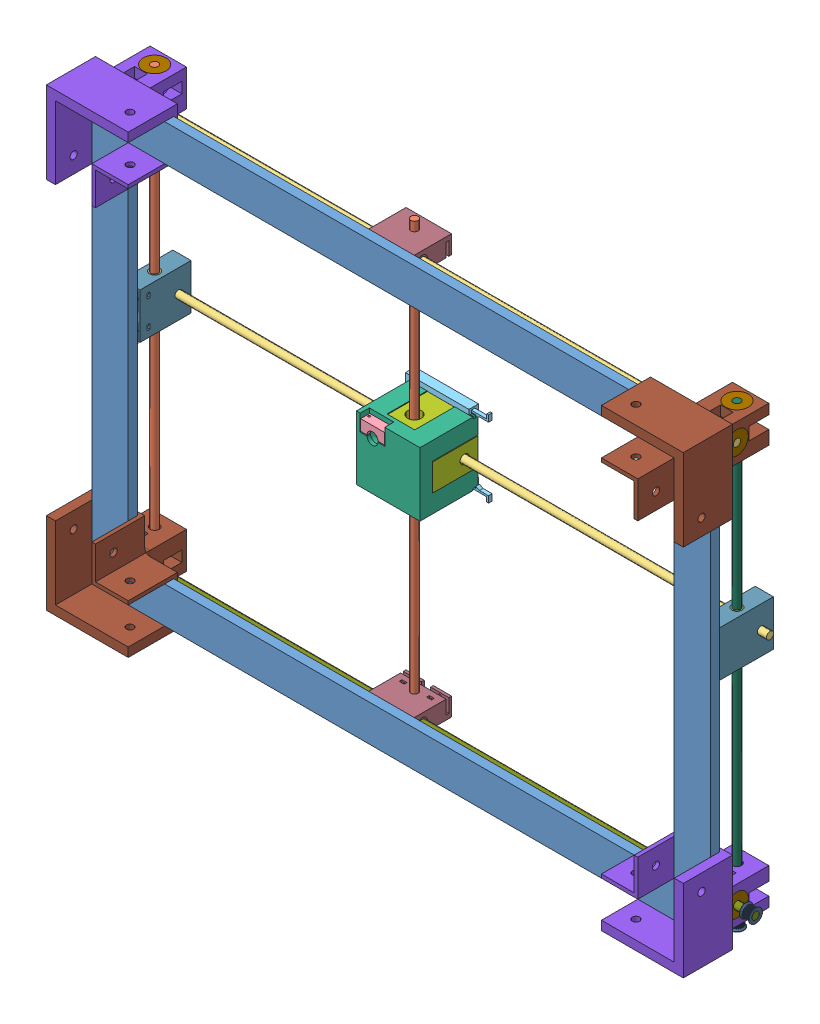
SolidWorks assembly Assemblage_XY, configuration Défaut. Lengths in mm.
Overall size (711.84 510.5 125.29).
50 component instances, 16 part files, 70 mates.
Components (placement in the parent):
- Cadre_XY-1: Cadre_XY [Défaut] at (379.0068 -247.2078 675) size (680 480 10)
- AXE_8X480-2: AXE_8X480 [Défaut] at (-280.9932 -247.2078 636) x (0.987721 0 0.156231) z (0 1 0) size (8 8 480)
- AXE_8X680-1: AXE_8X680 [Défaut] at (379.0068 212.7922 656) x (0 0.013067 0.999915) z (-1 0 0) size (8 8 680)
- AXE_8X480-3: AXE_8X480 [Défaut] at (8.3254 232.7922 639.7) x (0.999527 0 0.030742) z (0 -1 0) size (8 8 480)
- AXE_8X680-3: AXE_8X680 [Défaut] at (-300.9932 11.1319 619.7) x (0 -0.696158 -0.717888) z (1 0 0) size (8 8 680)
- P3DMIPC-Tête_complete-1: P3DMIPC-Tête_complete [Défaut] at (-35.8673 24.5019 635.2981) x (0 1 0) z (1 0 0) size (84 69 89)
  - P3DMIPC-Clip_Buse_E3D-1: P3DMIPC-Clip_Buse_E3D [Défaut] at (17.0518 23.4109 40.0035) x (1 0 0) z (0 1 0) size (12 26 10)
  - P3DMIPC-Clip_tête-1: P3DMIPC-Clip_tête [Défaut] at (26.9018 -25.0891 4.5597) x (1 0 0) z (0 -1 0) size (84 89 10.5)
  - P3DMIPC-Porte_Buse_E3DX1-1: P3DMIPC-Porte_Buse_E3DX1 [Défaut] at (22.03 33.4019 79.1927) x (0 0 1) z (0 -1 0) size (70 70 64)
  - P3DMIPC-Chariot-1: P3DMIPC-Chariot [Défaut] at (-48.37 -30.5981 79.1927) size (70 50 70)
- Angle_magique_G-1: Angle_magique_G [Défaut] at (379.0068 -247.2078 675) x (-1 0 0) z (0 0 -1) size (91.34 90 104)
- F608ZZ-1: F608ZZ [Défaut] at (372.0068 -227.2078 656) x (0 -0.924225 -0.381849) z (1 0 0) size (25 25 7)
- Angle_magique_G-4: Angle_magique_G [Défaut] at (-300.9932 232.7922 675) x (1 0 0) z (0 0 -1) size (91.34 90 104)
- pulley_gt2_3mm_20t-10: pulley_gt2_3mm_20t [Défaut] at (-280.9932 209.5422 636) x (0.106795 0 0.994281) z (0 1 0) size (15 15 10.5)
- pulley_gt2_3mm_20t-11: pulley_gt2_3mm_20t [Défaut] at (-277.7432 212.7922 656) x (0 0.106795 0.994281) z (-1 0 0) size (15 15 10.5)
- pulley_gt2_3mm_20t-12: pulley_gt2_3mm_20t [Défaut] at (-280.9932 -236.4578 636) x (-0.771074 0 0.636745) z (0 1 0) size (15 15 10.5)
- pulley_gt2_3mm_20t-13: pulley_gt2_3mm_20t [Défaut] at (-277.7432 -227.2078 656) x (0 0.106795 0.994281) z (-1 0 0) size (15 15 10.5)
- pulley_gt2_3mm_20t-15: pulley_gt2_3mm_20t [Défaut] at (359.0068 222.0422 636) x (-0.106795 0 0.994281) z (0 -1 0) size (15 15 10.5)
- pulley_gt2_3mm_20t-16: pulley_gt2_3mm_20t [Défaut] at (368.2568 212.7922 656) x (0 0.106795 0.994281) z (-1 0 0) size (15 15 10.5)
- F608ZZ-2: F608ZZ [Défaut] at (-280.9932 225.7922 636) x (-0.546944 0 0.837169) z (0 1 0) size (25 25 7)
- F608ZZ-3: F608ZZ [Défaut] at (-293.9932 212.7922 656) x (0 0 1) z (-1 0 0) size (25 25 7)
- F608ZZ-4: F608ZZ [Défaut] at (-293.9932 -227.2078 656) x (0 0 1) z (-1 0 0) size (25 25 7)
- F608ZZ-5: F608ZZ [Défaut] at (-280.9932 -240.2078 636) x (-0.924225 0 -0.381849) z (0 -1 0) size (25 25 7)
- F608ZZ-6: F608ZZ [Défaut] at (359.0068 -240.2078 636) x (-0.546944 0 0.837169) z (0 -1 0) size (25 25 7)
- F608ZZ-7: F608ZZ [Défaut] at (372.0068 212.7922 656) x (0 0 1) z (1 0 0) size (25 25 7)
- F608ZZ-8: F608ZZ [Défaut] at (359.0068 225.7922 636) x (0 0 1) z (0 1 0) size (25 25 7)
- Angle_magique_D-1: Angle_magique_D [Défaut] at (-300.9932 -247.2078 675) x (0 1 0) z (0 0 -1) size (90 91.34 104)
- Angle_magique_D-2: Angle_magique_D [Défaut] at (379.0068 232.7922 675) x (0 -1 0) z (0 0 -1) size (90 91.34 104)
- Assemblage_glissière_block_belt_palier_AR-1: Assemblage_glissière_block_belt_palier_AR [Défaut] at (128.8503 -186.4667 609.4689) x (0 -1 0) z (-1 0 0) size (20 42 50)
  - ultimaker_cuivre_fritté_douille_8mmx11mmx22 mm-1: ultimaker_cuivre_fritté_douille_8mmx11mmx22 mm [Défaut] at (40.7411 46.5311 95.5249) size (11 11 22)
  - ultimaker_cuivre_fritté_douille_8mmx11mmx22 mm-2: ultimaker_cuivre_fritté_douille_8mmx11mmx22 mm [Défaut] at (40.7411 46.5311 123.5249) size (11 11 22)
  - Glisière_block_belt_AR-2: Glisière_block_belt_AR [Défaut] at (50.7411 14.5311 95.5249) size (20 42 50)
- Assemblage_glissière_block_belt_palier_AR-2: Assemblage_glissière_block_belt_palier_AR [Défaut] at (-112.1995 172.0511 609.4689) x (0 1 0) z (1 0 0) size (20 42 50)
  - ultimaker_cuivre_fritté_douille_8mmx11mmx22 mm-1: ultimaker_cuivre_fritté_douille_8mmx11mmx22 mm [Défaut] at (40.7411 46.5311 95.5249) size (11 11 22)
  - ultimaker_cuivre_fritté_douille_8mmx11mmx22 mm-2: ultimaker_cuivre_fritté_douille_8mmx11mmx22 mm [Défaut] at (40.7411 46.5311 123.5249) size (11 11 22)
  - Glisière_block_belt_AR-2: Glisière_block_belt_AR [Défaut] at (50.7411 14.5311 95.5249) size (20 42 50)
- pulley_gt2_3mm_20t-17: pulley_gt2_3mm_20t [Défaut] at (368.2568 -227.2078 656) x (0 0.106795 0.994281) z (-1 0 0) size (15 15 10.5)
- pulley_gt2_3mm_20t-18: pulley_gt2_3mm_20t [Défaut] at (359.0068 -223.9578 636) x (0.203502 0 0.979074) z (0 -1 0) size (15 15 10.5)
- Assemblage_glissière_block_belt_palier_GD-1: Assemblage_glissière_block_belt_palier_GD [Défaut] at (364.4936 -63.8681 626.6132) x (-1 0 0) z (0 1 0) size (20 60 50)
  - Glisière_block_belt_GD-1: Glisière_block_belt_GD [Défaut] at (15.4869 -20.6132 50) size (20 60 50)
  - ultimaker_cuivre_fritté_douille_8mmx11mmx22 mm-1: ultimaker_cuivre_fritté_douille_8mmx11mmx22 mm [Défaut] at (5.4869 9.3868 50) size (11 11 22)
  - ultimaker_cuivre_fritté_douille_8mmx11mmx22 mm-2: ultimaker_cuivre_fritté_douille_8mmx11mmx22 mm [Défaut] at (5.4869 9.3868 78) size (11 11 22)
- Assemblage_glissière_block_belt_palier_GD-2: Assemblage_glissière_block_belt_palier_GD [Défaut] at (-286.4801 86.1319 626.6132) x (1 0 0) z (0 -1 0) size (20 60 50)
  - Glisière_block_belt_GD-1: Glisière_block_belt_GD [Défaut] at (15.4869 -20.6132 50) size (20 60 50)
  - ultimaker_cuivre_fritté_douille_8mmx11mmx22 mm-1: ultimaker_cuivre_fritté_douille_8mmx11mmx22 mm [Défaut] at (5.4869 9.3868 50) size (11 11 22)
  - ultimaker_cuivre_fritté_douille_8mmx11mmx22 mm-2: ultimaker_cuivre_fritté_douille_8mmx11mmx22 mm [Défaut] at (5.4869 9.3868 78) size (11 11 22)
- AXE_8X500_Moteur-1: AXE_8X500_Moteur [Défaut] at (359.0068 -267.7078 636) x (0.283264 0 -0.959042) z (0 1 0) size (8 8 500.5)
- AXE_8X700_Moteur-1: AXE_8X700_Moteur [Défaut] at (399.5068 -227.2078 656) x (0 0 1) z (-1 0 0) size (8 8 700.5)
- pulley_gt2_3mm_20t-19: pulley_gt2_3mm_20t [Défaut] at (359.0068 -256.2078 636) x (0.203502 0 0.979074) z (0 -1 0) size (15 15 10.5)
- pulley_gt2_3mm_20t-20: pulley_gt2_3mm_20t [Défaut] at (388.0068 -227.2078 656) x (0 0.203502 0.979074) z (1 0 0) size (15 15 10.5)
Mates (geometry in assembly coordinates):
- Coaxiale1: concentric anti-aligned: cylinder of AXE_8X680-3 through (379.0068 11.1319 619.7) axis (-1 0 0) radius 4; cylinder of P3DMIPC-Tête_complete-1/P3DMIPC-Chariot-1 through (39.3254 11.1319 619.7) axis (1 0 0) radius 5
- Coaxiale2: concentric anti-aligned: cylinder of AXE_8X480-3 through (8.3254 -247.2078 639.7) axis (0 1 0) radius 4; cylinder of P3DMIPC-Tête_complete-1/P3DMIPC-Chariot-1 through (8.3254 -19.8681 639.7) axis (0 -1 0) radius 5
- Coïncidente14: coincident anti-aligned: plane of Cadre_XY-1 through (379.0068 -247.2078 675) normal (0 0 -1); plane of Angle_magique_G-1 through (379.0068 -247.2078 675) normal (0 0 1)
- Coïncidente15: coincident anti-aligned: plane of Cadre_XY-1 through (379.0068 -247.2078 685) normal (1 0 0); plane of Angle_magique_G-1 through (379.0068 -247.2078 725) normal (-1 0 0)
- Coïncidente16: coincident anti-aligned: plane of Cadre_XY-1 through (379.0068 -247.2078 685) normal (0 -1 0); plane of Angle_magique_G-1 through (299.0068 -247.2078 725) normal (0 1 0)
- Coïncidente27: coincident anti-aligned: plane of Cadre_XY-1 through (379.0068 -247.2078 675) normal (0 0 -1); plane of Angle_magique_G-4 through (-300.9932 232.7922 675) normal (0 0 1)
- Coïncidente28: coincident anti-aligned: plane of Cadre_XY-1 through (379.0068 232.7922 685) normal (0 1 0); plane of Angle_magique_G-4 through (-220.9932 232.7922 725) normal (0 -1 0)
- Coïncidente29: coincident anti-aligned: plane of Cadre_XY-1 through (-300.9932 -247.2078 685) normal (-1 0 0); plane of Angle_magique_G-4 through (-300.9932 232.7922 725) normal (1 0 0)
- Coaxiale17: concentric anti-aligned: cylinder of AXE_8X680-1 through (-300.9932 212.7922 656) axis (1 0 0) radius 4; cylinder of pulley_gt2_3mm_20t-11 through (-277.7432 212.7922 656) axis (-1 0 0) radius 4
- Coaxiale18: concentric aligned: cylinder of AXE_8X680-1 through (-300.9932 212.7922 656) axis (1 0 0) radius 4; cylinder of Angle_magique_G-4 through (-310.9932 212.7922 656) axis (1 0 0) radius 5
- Coïncidente30: coincident aligned: plane of Cadre_XY-1 through (-300.9932 -247.2078 685) normal (-1 0 0); plane of AXE_8X680-1 through (-300.9932 212.7922 656) normal (-1 0 0)
- Distance2: distance = 2.75 mm anti-aligned: plane of pulley_gt2_3mm_20t-11 through (-278.7432 212.7922 656) normal (1 0 0); plane of Angle_magique_G-4 through (-275.9932 192.7922 621) normal (-1 0 0)
- Coaxiale19: concentric anti-aligned: cylinder of AXE_8X680-1 through (-300.9932 212.7922 656) axis (1 0 0) radius 4; cylinder of pulley_gt2_3mm_20t-16 through (368.2568 212.7922 656) axis (-1 0 0) radius 4
- Coaxiale24: concentric aligned: cylinder of AXE_8X480-2 through (-280.9932 232.7922 636) axis (0 -1 0) radius 4; cylinder of Angle_magique_G-4 through (-280.9932 232.7923 636) axis (0 -1 0) radius 5
- Coaxiale25: concentric anti-aligned: cylinder of AXE_8X480-2 through (-280.9932 232.7922 636) axis (0 -1 0) radius 4; cylinder of pulley_gt2_3mm_20t-10 through (-280.9932 209.5422 636) axis (0 1 0) radius 4
- Coïncidente34: coincident aligned: plane of Cadre_XY-1 through (379.0068 232.7922 685) normal (0 1 0); plane of AXE_8X480-2 through (-280.9932 232.7922 636) normal (0 1 0)
- Distance4: distance = 2.75 mm anti-aligned: plane of pulley_gt2_3mm_20t-10 through (-280.9932 210.5422 636) normal (0 -1 0); plane of Angle_magique_G-4 through (-275.9932 207.7922 621) normal (0 1 0)
- Coaxiale26: concentric anti-aligned: cylinder of AXE_8X480-2 through (-280.9932 232.7922 636) axis (0 -1 0) radius 4; cylinder of pulley_gt2_3mm_20t-12 through (-280.9932 -236.4578 636) axis (0 1 0) radius 4
- Coïncidente44: coincident anti-aligned: plane of Cadre_XY-1 through (379.0068 -247.2078 675) normal (0 0 -1); plane of Angle_magique_D-1 through (-300.9932 -247.2078 675) normal (0 0 1)
- Coïncidente45: coincident anti-aligned: plane of Cadre_XY-1 through (379.0068 -247.2078 685) normal (0 -1 0); plane of Angle_magique_D-1 through (-300.9932 -247.2078 725) normal (0 1 0)
- Coïncidente46: coincident anti-aligned: plane of Cadre_XY-1 through (-300.9932 -247.2078 685) normal (-1 0 0); plane of Angle_magique_D-1 through (-300.9932 -167.2078 725) normal (1 0 0)
- Distance10: distance = 2.75 mm anti-aligned: plane of Angle_magique_D-1 through (-260.9932 -222.2078 621) normal (0 -1 0); plane of pulley_gt2_3mm_20t-12 through (-280.9932 -224.9578 636) normal (0 1 0)
- Coïncidente51: coincident anti-aligned: plane of Cadre_XY-1 through (379.0068 -247.2078 675) normal (0 0 -1); plane of Angle_magique_D-2 through (379.0068 232.7922 675) normal (0 0 1)
- Coïncidente52: coincident anti-aligned: plane of Cadre_XY-1 through (379.0068 232.7922 685) normal (0 1 0); plane of Angle_magique_D-2 through (379.0068 232.7922 725) normal (0 -1 0)
- Coïncidente53: coincident anti-aligned: plane of Cadre_XY-1 through (379.0068 -247.2078 685) normal (1 0 0); plane of Angle_magique_D-2 through (379.0068 152.7922 725) normal (-1 0 0)
- Distance11: distance = 2.75 mm anti-aligned: plane of pulley_gt2_3mm_20t-15 through (359.0068 210.5422 636) normal (0 -1 0); plane of Angle_magique_D-2 through (339.0068 207.7922 621) normal (0 1 0)
- Distance12: distance = 2.75 mm anti-aligned: plane of Angle_magique_D-2 through (354.0068 207.7922 621) normal (1 0 0); plane of pulley_gt2_3mm_20t-16 through (356.7568 212.7922 656) normal (-1 0 0)
- Coaxiale39: concentric anti-aligned: cylinder of AXE_8X680-1 through (-300.9932 212.7922 656) axis (1 0 0) radius 4; cylinder of Assemblage_glissière_block_belt_palier_AR-2/ultimaker_cuivre_fritté_douille_8mmx11mmx22 mm-1 through (5.3254 212.7922 656) axis (-1 0 0) radius 4
- Coaxiale42: concentric anti-aligned: cylinder of AXE_8X480-3 through (8.3254 -247.2078 639.7) axis (0 1 0) radius 4; cylinder of Assemblage_glissière_block_belt_palier_AR-2/Glisière_block_belt_AR-2 through (8.3254 222.7922 639.7) axis (0 -1 0) radius 4
- Coaxiale43: concentric aligned: cylinder of AXE_8X480-3 through (8.3254 -247.2078 639.7) axis (0 1 0) radius 4; cylinder of Assemblage_glissière_block_belt_palier_AR-1/Glisière_block_belt_AR-2 through (8.3254 -237.2078 639.7) axis (0 1 0) radius 4
- Coaxiale50: concentric anti-aligned: cylinder of F608ZZ-7 through (377.5068 212.7922 656) axis (-1 0 0) radius 11; cylinder of Angle_magique_D-2 through (372.0068 212.7922 656) axis (1 0 0) radius 11
- Coïncidente63: coincident anti-aligned: plane of F608ZZ-7 through (372.0068 212.7922 656) normal (-1 0 0); plane of Angle_magique_D-2 through (372.0068 212.7922 656) normal (1 0 0)
- Coaxiale51: concentric anti-aligned: cylinder of F608ZZ-8 through (359.0068 231.2922 636) axis (0 -1 0) radius 11; cylinder of Angle_magique_D-2 through (359.0068 225.7922 636) axis (0 1 0) radius 11
- Coïncidente64: coincident anti-aligned: plane of F608ZZ-8 through (359.0068 225.7922 636) normal (0 -1 0); plane of Angle_magique_D-2 through (359.0068 225.7922 636) normal (0 1 0)
- Coïncidente65: coincident anti-aligned: plane of Angle_magique_G-4 through (-280.9932 225.7922 636) normal (0 1 0); plane of F608ZZ-2 through (-280.9932 225.7922 636) normal (0 -1 0)
- Coaxiale53: concentric anti-aligned: cylinder of Angle_magique_G-4 through (-280.9932 225.7922 636) axis (0 1 0) radius 11; cylinder of F608ZZ-2 through (-280.9932 231.2922 636) axis (0 -1 0) radius 11
- Coaxiale54: concentric anti-aligned: cylinder of Angle_magique_G-4 through (-293.9932 212.7922 656) axis (-1 0 0) radius 11; cylinder of F608ZZ-3 through (-299.4932 212.7922 656) axis (1 0 0) radius 11
- Coïncidente66: coincident anti-aligned: plane of Angle_magique_G-4 through (-293.9932 212.7922 656) normal (-1 0 0); plane of F608ZZ-3 through (-293.9932 212.7922 656) normal (1 0 0)
- Coaxiale57: concentric anti-aligned: cylinder of F608ZZ-4 through (-299.4932 -227.2078 656) axis (1 0 0) radius 11; cylinder of Angle_magique_D-1 through (-293.9932 -227.2078 656) axis (-1 0 0) radius 11
- Coïncidente69: coincident anti-aligned: plane of F608ZZ-4 through (-293.9932 -227.2078 656) normal (1 0 0); plane of Angle_magique_D-1 through (-293.9932 -227.2078 656) normal (-1 0 0)
- Coïncidente70: coincident anti-aligned: plane of F608ZZ-5 through (-280.9932 -240.2078 636) normal (0 1 0); plane of Angle_magique_D-1 through (-280.9932 -240.2078 636) normal (0 -1 0)
- Coaxiale58: concentric anti-aligned: cylinder of F608ZZ-5 through (-280.9932 -245.7078 636) axis (0 1 0) radius 11; cylinder of Angle_magique_D-1 through (-280.9932 -240.2078 636) axis (0 -1 0) radius 11
- Distance14: distance = 2.75 mm anti-aligned: plane of Angle_magique_G-1 through (354.0068 -222.2078 621) normal (0 -1 0); plane of pulley_gt2_3mm_20t-18 through (359.0068 -224.9578 636) normal (0 1 0)
- Distance15: distance = 2.75 mm anti-aligned: plane of Angle_magique_G-1 through (354.0068 -207.2078 621) normal (1 0 0); plane of pulley_gt2_3mm_20t-17 through (356.7568 -227.2078 656) normal (-1 0 0)
- Coïncidente73: coincident anti-aligned: plane of Angle_magique_G-1 through (359.0068 -240.2078 636) normal (0 -1 0); plane of F608ZZ-6 through (359.0068 -240.2078 636) normal (0 1 0)
- Coaxiale61: concentric anti-aligned: cylinder of Angle_magique_G-1 through (359.0068 -240.2078 636) axis (0 -1 0) radius 11; cylinder of F608ZZ-6 through (359.0068 -245.7078 636) axis (0 1 0) radius 11
- Coïncidente74: coincident anti-aligned: plane of Angle_magique_G-1 through (372.0068 -227.2078 656) normal (1 0 0); plane of F608ZZ-1 through (372.0068 -227.2078 656) normal (-1 0 0)
- Coaxiale62: concentric anti-aligned: cylinder of Angle_magique_G-1 through (372.0068 -227.2078 656) axis (1 0 0) radius 11; cylinder of F608ZZ-1 through (377.5068 -227.2078 656) axis (-1 0 0) radius 11
- Coaxiale64: concentric anti-aligned: cylinder of AXE_8X680-3 through (379.0068 11.1319 619.7) axis (-1 0 0) radius 4; cylinder of Assemblage_glissière_block_belt_palier_GD-1/Glisière_block_belt_GD-1 through (349.0068 11.1319 619.7) axis (1 0 0) radius 4
- Coaxiale65: concentric anti-aligned: cylinder of Assemblage_glissière_block_belt_palier_GD-2/ultimaker_cuivre_fritté_douille_8mmx11mmx22 mm-1 through (-280.9932 14.1319 636) axis (0 1 0) radius 4; cylinder of AXE_8X480-2 through (-280.9932 232.7922 636) axis (0 -1 0) radius 4
- Coaxiale66: concentric aligned: cylinder of AXE_8X680-3 through (379.0068 11.1319 619.7) axis (-1 0 0) radius 4; cylinder of Assemblage_glissière_block_belt_palier_GD-2/Glisière_block_belt_GD-1 through (-270.9932 11.1319 619.7) axis (-1 0 0) radius 4
- Coïncidente75: coincident aligned: plane of Cadre_XY-1 through (-300.9932 -247.2078 685) normal (-1 0 0); plane of AXE_8X680-3 through (-300.9932 11.1319 619.7) normal (-1 0 0)
- Coïncidente76: coincident aligned: plane of Cadre_XY-1 through (379.0068 -247.2078 685) normal (0 -1 0); plane of AXE_8X480-3 through (8.3254 -247.2078 639.7) normal (0 -1 0)
- Distance17: distance = 2.75 mm anti-aligned: plane of pulley_gt2_3mm_20t-13 through (-278.7432 -227.2078 656) normal (1 0 0); plane of Angle_magique_D-1 through (-275.9932 -222.2078 621) normal (-1 0 0)
- Coaxiale67: concentric anti-aligned: cylinder of Angle_magique_G-1 through (389.0068 -227.2078 656) axis (-1 0 0) radius 5; cylinder of AXE_8X700_Moteur-1 through (-300.9932 -227.2078 656) axis (1 0 0) radius 4
- Coaxiale68: concentric aligned: cylinder of Assemblage_glissière_block_belt_palier_AR-1/ultimaker_cuivre_fritté_douille_8mmx11mmx22 mm-2 through (-16.6746 -227.2078 656) axis (1 0 0) radius 4; cylinder of AXE_8X700_Moteur-1 through (-300.9932 -227.2078 656) axis (1 0 0) radius 4
- Coaxiale69: concentric aligned: cylinder of Angle_magique_D-1 through (-310.9932 -227.2078 656) axis (1 0 0) radius 5; cylinder of AXE_8X700_Moteur-1 through (-300.9932 -227.2078 656) axis (1 0 0) radius 4
- Coïncidente80: coincident aligned: plane of Cadre_XY-1 through (-300.9932 -247.2078 685) normal (-1 0 0); plane of AXE_8X700_Moteur-1 through (-300.9932 -227.2078 656) normal (-1 0 0)
- Coaxiale70: concentric anti-aligned: cylinder of pulley_gt2_3mm_20t-13 through (-277.7432 -227.2078 656) axis (-1 0 0) radius 4; cylinder of AXE_8X700_Moteur-1 through (-300.9932 -227.2078 656) axis (1 0 0) radius 4
- Coaxiale71: concentric anti-aligned: cylinder of pulley_gt2_3mm_20t-17 through (368.2568 -227.2078 656) axis (-1 0 0) radius 4; cylinder of AXE_8X700_Moteur-1 through (-300.9932 -227.2078 656) axis (1 0 0) radius 4
- Coaxiale72: concentric aligned: cylinder of Assemblage_glissière_block_belt_palier_GD-1/ultimaker_cuivre_fritté_douille_8mmx11mmx22 mm-2 through (359.0068 36.1319 636) axis (0 -1 0) radius 4; cylinder of AXE_8X500_Moteur-1 through (359.0068 232.7922 636) axis (0 -1 0) radius 4
- Coaxiale73: concentric anti-aligned: cylinder of Angle_magique_G-1 through (359.0068 -247.2078 636) axis (0 1 0) radius 5; cylinder of AXE_8X500_Moteur-1 through (359.0068 232.7922 636) axis (0 -1 0) radius 4
- Coaxiale74: concentric aligned: cylinder of Angle_magique_D-2 through (359.0068 242.7922 636) axis (0 -1 0) radius 5; cylinder of AXE_8X500_Moteur-1 through (359.0068 232.7922 636) axis (0 -1 0) radius 4
- Coaxiale75: concentric aligned: cylinder of pulley_gt2_3mm_20t-15 through (359.0068 222.0422 636) axis (0 -1 0) radius 4; cylinder of AXE_8X500_Moteur-1 through (359.0068 232.7922 636) axis (0 -1 0) radius 4
- Coaxiale76: concentric aligned: cylinder of pulley_gt2_3mm_20t-18 through (359.0068 -223.9578 636) axis (0 -1 0) radius 4; cylinder of AXE_8X500_Moteur-1 through (359.0068 232.7922 636) axis (0 -1 0) radius 4
- Coïncidente81: coincident aligned: plane of Cadre_XY-1 through (379.0068 232.7922 685) normal (0 1 0); plane of AXE_8X500_Moteur-1 through (359.0068 232.7922 636) normal (0 1 0)
- Coaxiale77: concentric aligned: cylinder of AXE_8X500_Moteur-1 through (359.0068 232.7922 636) axis (0 -1 0) radius 4; cylinder of pulley_gt2_3mm_20t-19 through (359.0068 -256.2078 636) axis (0 -1 0) radius 4
- Coïncidente82: coincident aligned: plane of AXE_8X500_Moteur-1 through (359.0068 -267.7078 636) normal (0 -1 0); plane of pulley_gt2_3mm_20t-19 through (359.0068 -267.7078 636) normal (0 -1 0)
- Coïncidente83: coincident aligned: plane of AXE_8X700_Moteur-1 through (399.5068 -227.2078 656) normal (1 0 0); plane of pulley_gt2_3mm_20t-20 through (399.5068 -227.2078 656) normal (1 0 0)
- Coaxiale78: concentric aligned: cylinder of AXE_8X700_Moteur-1 through (-300.9932 -227.2078 656) axis (1 0 0) radius 4; cylinder of pulley_gt2_3mm_20t-20 through (388.0068 -227.2078 656) axis (1 0 0) radius 4
